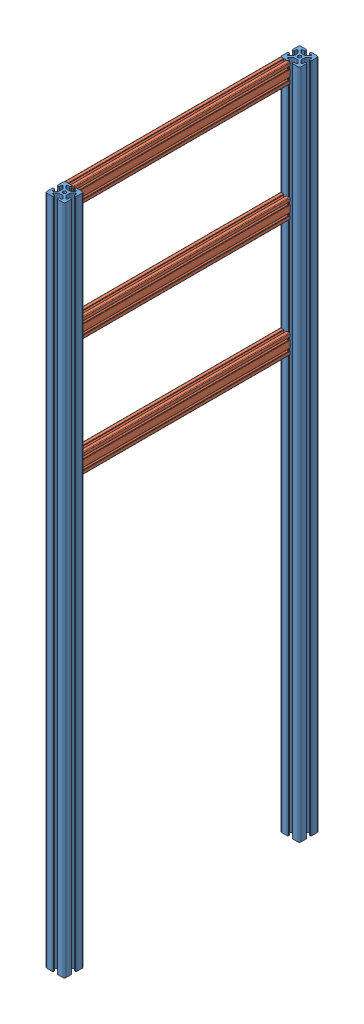
SolidWorks assembly Frame Front_or_Back, configuration Default. Lengths in mm.
Overall size (40 1400 530).
5 component instances, 2 part files, 12 mates.
Components (placement in the parent):
- 40_4040_1400_CL-1: 40_4040_1400_CL [Default] at (1052.7748 163.6702 421.9179) x (1 0 0) z (0 -1 0) size (40 40 1400)
- 40_4040_1400_CL-2: 40_4040_1400_CL [Default] at (1052.7748 163.6702 -68.0821) x (1 0 0) z (0 -1 0) size (40 40 1400)
- 20_2040_450_CL-1: 20_2040_450_CL [Default] at (1042.7748 1533.6702 401.9179) size (20 40 450)
- 20_2040_450_CL-2: 20_2040_450_CL [Default] at (1042.7748 1288.9702 401.9179) size (20 40 450)
- 20_2040_450_CL-3: 20_2040_450_CL [Default] at (1042.7748 1044.2702 401.9179) size (20 40 450)
Mates (geometry in assembly coordinates):
- Coincident1: coincident: plane of 40_4040_1400_CL-1 through (1035.9448 1563.6702 401.9179) normal (0 0 -1); plane of 20_2040_450_CL-1 through (1034.2748 1562.1702 401.9179) normal (0 0 1)
- Coincident2: coincident: plane of 40_4040_1400_CL-1 through (1032.7748 1563.6702 416.2275) normal (-1 0 0); plane of 20_2040_450_CL-1 through (1032.7748 1550.5322 -48.0821) normal (-1 0 0)
- Coincident3: coincident aligned: plane of 40_4040_1400_CL-1 through (1035.9448 1563.6702 438.7479) normal (0 1 0); plane of 20_2040_450_CL-1 through (1039.6368 1563.6702 -48.0821) normal (0 1 0)
- Coincident4: coincident: plane of 40_4040_1400_CL-2 through (1047.0843 1563.6702 -48.0821) normal (0 0 1); plane of 20_2040_450_CL-1 through (1034.2748 1562.1702 -48.0821) normal (0 0 -1)
- Coincident5: coincident: plane of 40_4040_1400_CL-2 through (1032.7748 1563.6702 -51.2521) normal (-1 0 0); plane of 20_2040_450_CL-1 through (1032.7748 1550.5322 -48.0821) normal (-1 0 0)
- Coincident6: coincident aligned: plane of 40_4040_1400_CL-2 through (1035.9448 1563.6702 -51.2521) normal (0 1 0); plane of 20_2040_450_CL-1 through (1039.6368 1563.6702 -48.0821) normal (0 1 0)
- Coincident7: coincident: plane of 40_4040_1400_CL-2 through (1047.0843 1563.6702 -48.0821) normal (0 0 1); plane of 20_2040_450_CL-2 through (1034.2748 1317.4702 -48.0821) normal (0 0 -1)
- Coincident8: coincident: plane of 40_4040_1400_CL-2 through (1032.7748 1563.6702 -51.2521) normal (-1 0 0); plane of 20_2040_450_CL-2 through (1032.7748 1305.8322 -48.0821) normal (-1 0 0)
- Distance1: distance = 204.7 mm anti-aligned: plane of 20_2040_450_CL-2 through (1039.6368 1318.9702 -48.0821) normal (0 1 0); plane of 20_2040_450_CL-1 through (1034.2748 1523.6702 -48.0821) normal (0 -1 0)
- Coincident10: coincident: plane of 40_4040_1400_CL-2 through (1047.0843 1563.6702 -48.0821) normal (0 0 1); plane of 20_2040_450_CL-3 through (1034.2748 1072.7702 -48.0821) normal (0 0 -1)
- Coincident11: coincident: plane of 40_4040_1400_CL-2 through (1032.7748 1563.6702 -51.2521) normal (-1 0 0); plane of 20_2040_450_CL-3 through (1032.7748 1061.1322 -48.0821) normal (-1 0 0)
- Distance2: distance = 204.7 mm anti-aligned: plane of 20_2040_450_CL-3 through (1039.6368 1074.2702 -48.0821) normal (0 1 0); plane of 20_2040_450_CL-2 through (1034.2748 1278.9702 -48.0821) normal (0 -1 0)
